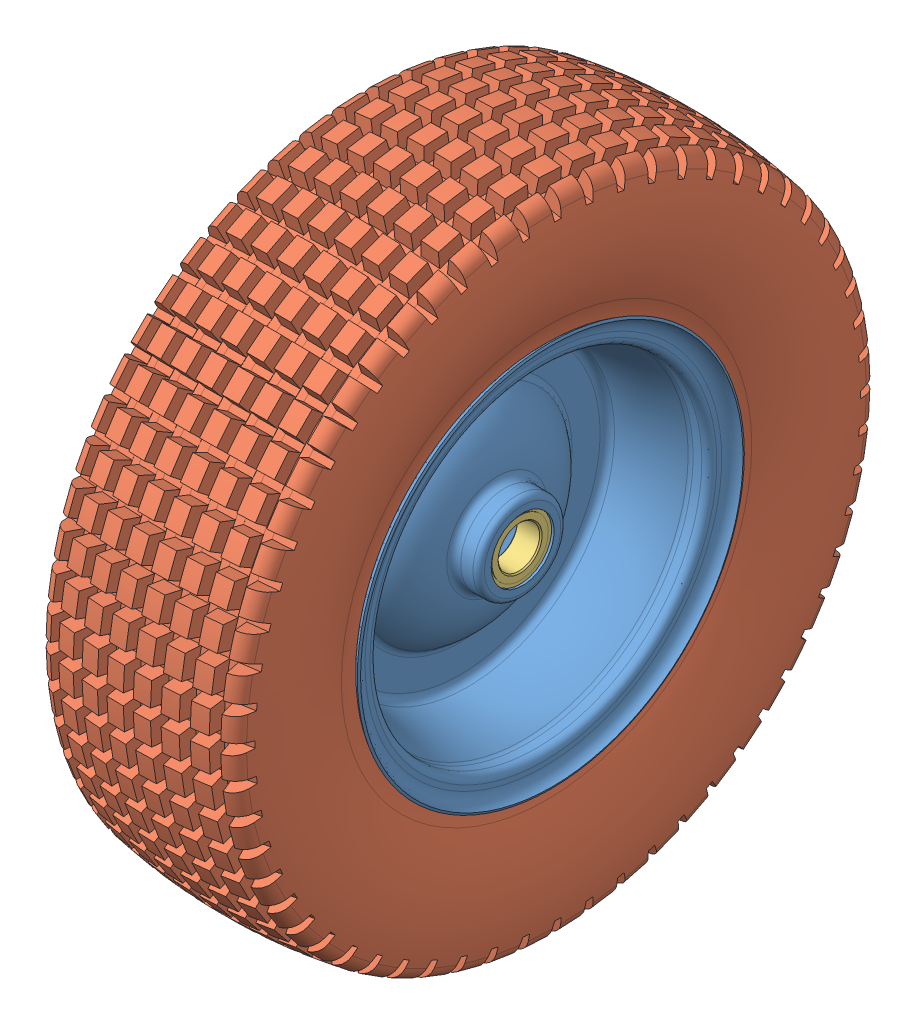
SolidWorks assembly Whellbarrow Wheel, configuration Default. Lengths in mm.
Overall size (124 398.25 398.25).
5 component instances, 3 part files, 9 mates.
Components (placement in the parent):
- Wheelbarrow Wheel half rim-1: Wheelbarrow Wheel half rim [Default] at origin size (56.6 233.53 233.53)
- Wheelbarrow Wheel half rim-2: Wheelbarrow Wheel half rim [Default] x (-1 0 0) z (0 -0.076485 -0.997071) size (56.6 233.53 233.53)
- wheel barrow tire-1: wheel barrow tire [Default] at origin size (124 398.25 398.25)
- 2349K424_Permanently Lubricated Ball Bearing-1: 2349K424_Permanently Lubricated Ball Bearing [2349K424] at (-30 0 0) x (0 0 1) z (-1 0 0) size (52 52 15)
- 2349K424_Permanently Lubricated Ball Bearing-2: 2349K424_Permanently Lubricated Ball Bearing [2349K424] at (30 0 0) x (0 0 1) z (-1 0 0) size (52 52 15)
Mates (geometry in assembly coordinates):
- Concentric1: concentric anti-aligned: cylinder of Wheelbarrow Wheel half rim-1 through (0 0 0) axis (-1 0 0) radius 25; cylinder of Wheelbarrow Wheel half rim-2 through (0 0 0) axis (1 0 0) radius 26.5
- Coincident1: coincident anti-aligned: plane of Wheelbarrow Wheel half rim-1 through (0 67.3202 0) normal (-1 0 0); plane of Wheelbarrow Wheel half rim-2 through (0 67.123 -5.149) normal (1 0 0)
- Concentric2: concentric aligned: cylinder of Wheelbarrow Wheel half rim-2 through (0 0 0) axis (1 0 0) radius 26.5; cylinder of wheel barrow tire-1 through (0 0 0) axis (1 0 0) radius 101.6
- Coincident3: coincident aligned: plane of Wheelbarrow Wheel half rim-1 through (0 0 0) normal (1 0 0); plane of wheel barrow tire-1 through (0 0 0) normal (1 0 0)
- Parallel1: parallel: plane of assembly through (0 0 0) normal (0 0 1); plane of Wheelbarrow Wheel half rim-1 through (0 0 0) normal (0 0 1); plane of assembly
- Concentric3: concentric anti-aligned: cylinder of Wheelbarrow Wheel half rim-2 through (0 0 0) axis (1 0 0) radius 25; cylinder of 2349K424_Permanently Lubricated Ball Bearing-1 through (-37.5 0 0) axis (-1 0 0) radius 26
- Coincident4: coincident anti-aligned: plane of Wheelbarrow Wheel half rim-2 through (-37.5 18.9443 -1.4532) normal (1 0 0); plane of 2349K424_Permanently Lubricated Ball Bearing-1 through (-37.5 13.25 0) normal (-1 0 0)
- Concentric4: concentric aligned: cylinder of Wheelbarrow Wheel half rim-1 through (0 0 0) axis (-1 0 0) radius 19; cylinder of 2349K424_Permanently Lubricated Ball Bearing-2 through (22.5 0 0) axis (-1 0 0) radius 12.5
- Coincident5: coincident anti-aligned: plane of Wheelbarrow Wheel half rim-1 through (37.5 19 0) normal (-1 0 0); plane of 2349K424_Permanently Lubricated Ball Bearing-2 through (37.5 13.25 0) normal (1 0 0)
